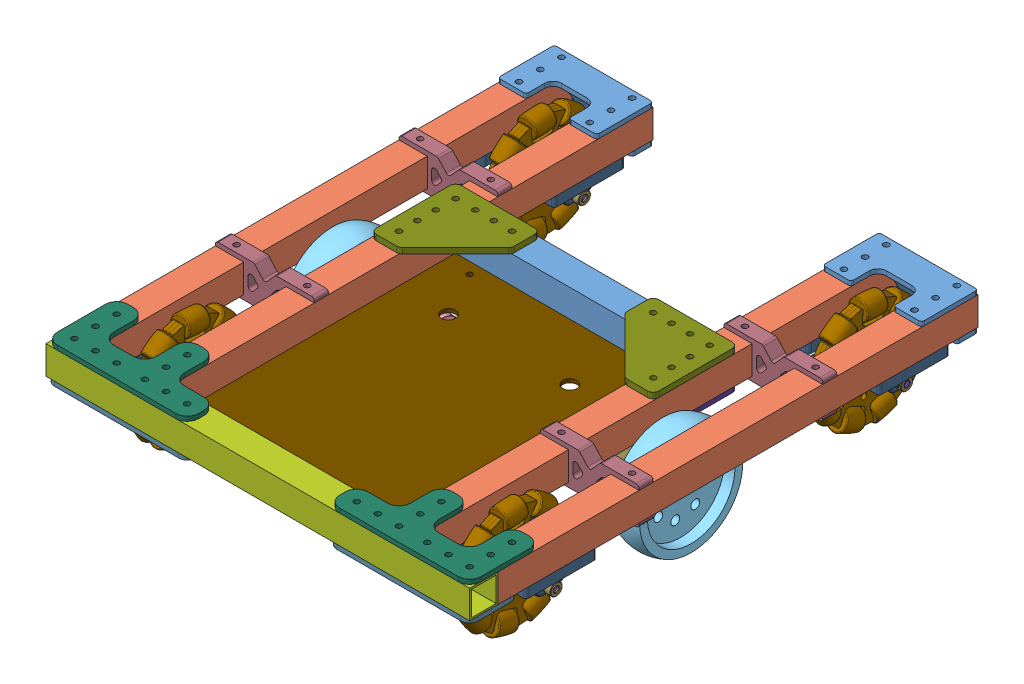
SolidWorks assembly Robot REV1, configuration Default. Lengths in mm.
Overall size (381 144.74 473.22).
69 component instances, 19 part files, 96 mates.
Components (placement in the parent):
- 1AL_8in-1: 1AL_8in [Default] at (-101.6 12.7 12.7) x (0 -1 0) z (0 0 1) size (25.4 203.2 25.4)
- 1AL_17in-1: 1AL_17in [Default] at (-114.3 12.7 -152.4) x (0 1 0) z (1 0 0) size (25.4 431.8 25.4)
- 1AL_17in-2: 1AL_17in [Default] at (114.3 12.7 279.4) x (0 -1 0) z (1 0 0) size (25.4 431.8 25.4)
- 1AL_17in-3: 1AL_17in [Default] at (-177.8 12.7 -152.4) x (0 1 0) z (1 0 0) size (25.4 431.8 25.4)
- 1AL_17in-4: 1AL_17in [Default] at (177.8 12.7 -152.4) x (1 0 0) z (0 -1 0) size (25.4 431.8 25.4)
- Motor mount-1: Motor mount [Default] at (114.7005 -22.3859 87.3407) x (0 0 -1) z (-1 0 0) size (72 44.98 12.7)
- 39530_txm-dc gearhead motor-1: 39530_txm-dc gearhead motor [Default] at (105 -22.5 76.2) x (0 0 1) z (0 1 0) size (37 99.15 37)
- 39055_txm-4 inch wheel-1: 39055_txm-4 inch wheel [Default] at (153.6244 -15.0231 100.1157) x (0 0.83426 0.551371) z (-1 0 0) size (97.6 97.6 25.4)
- 39079_txm-motor shaft hub with set screw-1: 39079_txm-motor shaft hub with set screw [Default] at (156.6976 -41.8931 64.5973) x (0 -0.551371 0.83426) z (-1 0 0) size (22 22 9.4)
- 39530_txm-dc gearhead motor-2: 39530_txm-dc gearhead motor [Default] at (-105 -22.5 76.2) x (0 0 -1) z (0 1 0) size (37 99.15 37)
- 39079_txm-motor shaft hub with set screw-2: 39079_txm-motor shaft hub with set screw [Default] at (-156.6976 -44.8973 83.3507) x (0 -0.263172 -0.964749) z (1 0 0) size (22 22 9.4)
- Motor mount-4: Motor mount [Default] at (-126.5995 -22.3859 87.3407) x (0 0 -1) z (-1 0 0) size (72 44.98 12.7)
- 39055_txm-4 inch wheel-2: 39055_txm-4 inch wheel [Default] at (-143.2256 -24.601 48.6766) x (0 -0.263172 -0.964749) z (-1 0 0) size (97.6 97.6 25.4)
- 1AL_15-2: 1AL_15 [Default] at (-190.5 12.7 292.1) x (0 -1 0) z (0 0 1) size (25.4 381 25.4)
- Omniwheel set-1: Omniwheel set [Default] at (-107.6288 -16.637 -92.837) x (0 0 -1) z (1 0 0) size (140.97 139.61 88.9)
  - 3in_Axel-1: 3in_Axel [Default] at (2.413 -2.413 -76.2) x (0.958428 0.285334 0) z (0.285334 -0.958428 0) size (4.83 76.2 4.83)
  - 4 inch omniwheel-2: 4 inch omniwheel [Default] at (5.0047 -4.3489 -46.041) x (-0.696661 0.7174 0) z (-0.7174 -0.696661 0) size (103.44 22.06 104.38)
  - 39079_txm-motor shaft hub with set screw-1: 39079_txm-motor shaft hub with set screw [Default] at (16.4027 7.2046 -45.1063) x (-0.696661 0.7174 0) z (0 0 1) size (22 22 9.4)
  - Omniwheel block-1: Omniwheel block [Default] at (2.413 16.637 -57.4712) x (1 0 0) z (0 1 0) size (63.5 25.4 27.33)
  - Wheel bushing-1: Wheel bushing [Default] at (-0.0381 -2.413 -57.046) size (9.52 9.53 12.7)
  - 39092_txm-axlesetcollars-1: 39092_txm-axlesetcollars [Default] at (2.6462 -2.783 -72.9038) x (0.992781 0.11994 0) z (0 0 1) size (11.66 11 6.2)
  - Omniwheel block-2: Omniwheel block [Default] at (2.413 16.637 -19.3712) x (-1 0 0) z (0 1 0) size (63.5 25.4 27.33)
  - Wheel bushing-2: Wheel bushing [Default] at (-0.0381 -2.413 -19.7964) x (1 0 0) z (0 0 -1) size (9.52 9.53 12.7)
  - 39092_txm-axlesetcollars-2: 39092_txm-axlesetcollars [Default] at (2.6002 -2.8083 -1.2602) size (11.66 11 6.2)
- Omniwheel set-2: Omniwheel set [Default] at (184.4712 -16.637 224.663) x (0 0 -1) z (1 0 0) size (140.97 139.61 88.9)
  - 3in_Axel-1: 3in_Axel [Default] at (2.413 -2.413 -76.2) x (0.958428 0.285334 0) z (0.285334 -0.958428 0) size (4.83 76.2 4.83)
  - 4 inch omniwheel-2: 4 inch omniwheel [Default] at (5.0047 -4.3489 -46.041) x (-0.696661 0.7174 0) z (-0.7174 -0.696661 0) size (103.44 22.06 104.38)
  - 39079_txm-motor shaft hub with set screw-1: 39079_txm-motor shaft hub with set screw [Default] at (16.4027 7.2046 -45.1063) x (-0.696661 0.7174 0) z (0 0 1) size (22 22 9.4)
  - Omniwheel block-1: Omniwheel block [Default] at (2.413 16.637 -57.4712) x (1 0 0) z (0 1 0) size (63.5 25.4 27.33)
  - Wheel bushing-1: Wheel bushing [Default] at (-0.0381 -2.413 -57.046) size (9.52 9.53 12.7)
  - 39092_txm-axlesetcollars-1: 39092_txm-axlesetcollars [Default] at (2.6462 -2.783 -72.9038) x (0.992781 0.11994 0) z (0 0 1) size (11.66 11 6.2)
  - Omniwheel block-2: Omniwheel block [Default] at (2.413 16.637 -19.3712) x (-1 0 0) z (0 1 0) size (63.5 25.4 27.33)
  - Wheel bushing-2: Wheel bushing [Default] at (-0.0381 -2.413 -19.7964) x (1 0 0) z (0 0 -1) size (9.52 9.53 12.7)
  - 39092_txm-axlesetcollars-2: 39092_txm-axlesetcollars [Default] at (2.6002 -2.8083 -1.2602) size (11.66 11 6.2)
- Omniwheel set-3: Omniwheel set [Default] at (107.6288 -16.637 -97.663) x (0 0 1) z (-1 0 0) size (140.97 139.61 88.9)
  - 3in_Axel-1: 3in_Axel [Default] at (2.413 -2.413 -76.2) x (0.958428 0.285334 0) z (0.285334 -0.958428 0) size (4.83 76.2 4.83)
  - 4 inch omniwheel-2: 4 inch omniwheel [Default] at (5.0047 -4.3489 -46.041) x (-0.696661 0.7174 0) z (-0.7174 -0.696661 0) size (103.44 22.06 104.38)
  - 39079_txm-motor shaft hub with set screw-1: 39079_txm-motor shaft hub with set screw [Default] at (16.4027 7.2046 -45.1063) x (-0.696661 0.7174 0) z (0 0 1) size (22 22 9.4)
  - Omniwheel block-1: Omniwheel block [Default] at (2.413 16.637 -57.4712) x (1 0 0) z (0 1 0) size (63.5 25.4 27.33)
  - Wheel bushing-1: Wheel bushing [Default] at (-0.0381 -2.413 -57.046) size (9.52 9.53 12.7)
  - 39092_txm-axlesetcollars-1: 39092_txm-axlesetcollars [Default] at (2.6462 -2.783 -72.9038) x (0.992781 0.11994 0) z (0 0 1) size (11.66 11 6.2)
  - Omniwheel block-2: Omniwheel block [Default] at (2.413 16.637 -19.3712) x (-1 0 0) z (0 1 0) size (63.5 25.4 27.33)
  - Wheel bushing-2: Wheel bushing [Default] at (-0.0381 -2.413 -19.7964) x (1 0 0) z (0 0 -1) size (9.52 9.53 12.7)
  - 39092_txm-axlesetcollars-2: 39092_txm-axlesetcollars [Default] at (2.6002 -2.8083 -1.2602) size (11.66 11 6.2)
- Omniwheel set-4: Omniwheel set [Default] at (-184.4712 -16.637 219.837) x (0 0 1) z (-1 0 0) size (140.97 139.61 88.9)
  - 3in_Axel-1: 3in_Axel [Default] at (2.413 -2.413 -76.2) x (0.958428 0.285334 0) z (0.285334 -0.958428 0) size (4.83 76.2 4.83)
  - 4 inch omniwheel-2: 4 inch omniwheel [Default] at (5.0047 -4.3489 -46.041) x (-0.696661 0.7174 0) z (-0.7174 -0.696661 0) size (103.44 22.06 104.38)
  - 39079_txm-motor shaft hub with set screw-1: 39079_txm-motor shaft hub with set screw [Default] at (16.4027 7.2046 -45.1063) x (-0.696661 0.7174 0) z (0 0 1) size (22 22 9.4)
  - Omniwheel block-1: Omniwheel block [Default] at (2.413 16.637 -57.4712) x (1 0 0) z (0 1 0) size (63.5 25.4 27.33)
  - Wheel bushing-1: Wheel bushing [Default] at (-0.0381 -2.413 -57.046) size (9.52 9.53 12.7)
  - 39092_txm-axlesetcollars-1: 39092_txm-axlesetcollars [Default] at (2.6462 -2.783 -72.9038) x (0.992781 0.11994 0) z (0 0 1) size (11.66 11 6.2)
  - Omniwheel block-2: Omniwheel block [Default] at (2.413 16.637 -19.3712) x (-1 0 0) z (0 1 0) size (63.5 25.4 27.33)
  - Wheel bushing-2: Wheel bushing [Default] at (-0.0381 -2.413 -19.7964) x (1 0 0) z (0 0 -1) size (9.52 9.53 12.7)
  - 39092_txm-axlesetcollars-2: 39092_txm-axlesetcollars [Default] at (2.6002 -2.8083 -1.2602) size (11.66 11 6.2)
- X Brace-1: X Brace [Default] at (-146.05 12.7 139.7) x (1 0 0) z (0 -1 0) size (88.9 12.7 33.4)
- X Brace-2: X Brace [Default] at (146.05 12.7 139.7) x (1 0 0) z (0 -1 0) size (88.9 12.7 33.4)
- X Brace-3: X Brace [Default] at (-146.05 12.7 -25.4) x (1 0 0) z (0 -1 0) size (88.9 12.7 33.4)
- X Brace-4: X Brace [Default] at (146.05 12.7 -25.4) x (1 0 0) z (0 -1 0) size (88.9 12.7 33.4)
- F Bracket1.0 3D-6: F Bracket1.0 3D [Default] at (0 -29.4 0) size (127 4 59.82)
- F Bracket1.0 3D-7: F Bracket1.0 3D [Default] at (0 25.4 0) x (-1 0 0) z (0 0 1) size (127 4 59.82)
- F Bracket D-5: F Bracket D [Default] at origin size (127 4 63.5)
- F Bracket D-6: F Bracket D [Default] at (0 54.8 0) x (-1 0 0) z (0 0 1) size (127 4 63.5)
- DXF L bracket-1: DXF L bracket [Default] at (127 25.4 0) x (-1 0 0) z (0 0 -1) size (76.2 5.08 76.2)
- DXF L bracket-2: DXF L bracket [Default] at (-127 25.4 0) x (0 0 1) z (-1 0 0) size (76.2 5.08 76.2)
- FIT bracket 3D-1: FIT bracket 3D [Default] at origin size (63.5 4 50.8)
- FIT bracket 3D-2: FIT bracket 3D [Default] at (0 -4 0) x (-1 0 0) z (0 0 1) size (63.5 4 50.8)
- ELE plexi-1: ELE plexi [Default] x (1 0 0) z (0 1 0) size (198.12 248.92 3.17)
- End Cap-1: End Cap [Default] at (177.8 25.4 -152.4) x (-1 0 0) z (0 1 0) size (88.9 50.8 33.4)
- End Cap-2: End Cap [Default] at (-114.3 25.4 -152.4) x (-1 0 0) z (0 1 0) size (88.9 50.8 33.4)
Mates (geometry in assembly coordinates):
- Coincident1: coincident anti-aligned: plane of 1AL_8in-1 through (101.6 0 0) normal (0 -1 0); plane of assembly through (0 0 0) normal (0 1 0)
- Coincident2: coincident anti-aligned: plane of 1AL_8in-1 through (101.6 0 0) normal (0 0 -1); plane of assembly through (0 0 0) normal (0 0 1)
- Distance2: distance = 101.6 mm anti-aligned: plane of assembly through (0 0 0) normal (1 0 0); plane of 1AL_8in-1 through (-101.6 12.7 12.7) normal (-1 0 0)
- Coincident4: coincident aligned: plane of 1AL_8in-1 through (101.6 25.4 0) normal (0 1 0); plane of 1AL_17in-1 through (-101.6 25.4 279.4) normal (0 1 0)
- Coincident5: coincident anti-aligned: plane of 1AL_8in-1 through (-101.6 12.7 12.7) normal (-1 0 0); plane of 1AL_17in-1 through (-101.6 25.4 279.4) normal (1 0 0)
- Coincident6: coincident aligned: plane of 1AL_8in-1 through (101.6 25.4 0) normal (0 1 0); plane of 1AL_17in-2 through (127 25.4 -152.4) normal (0 1 0)
- Coincident7: coincident anti-aligned: plane of 1AL_8in-1 through (101.6 12.7 12.7) normal (1 0 0); plane of 1AL_17in-2 through (101.6 0 -152.4) normal (-1 0 0)
- Coincident8: coincident aligned: plane of 1AL_17in-1 through (-114.3 12.7 -152.4) normal (0 0 -1); plane of 1AL_17in-2 through (114.3 12.7 -152.4) normal (0 0 -1)
- Distance3: distance = 152.4 mm aligned: plane of 1AL_17in-2 through (114.3 12.7 -152.4) normal (0 0 -1); plane of 1AL_8in-1 through (101.6 0 0) normal (0 0 -1)
- Distance4: distance = 38.1 mm anti-aligned: plane of 1AL_17in-1 through (-127 25.4 279.4) normal (-1 0 0); plane of 1AL_17in-3 through (-165.1 25.4 279.4) normal (1 0 0)
- Coincident11: coincident: line of 1AL_17in-1 through (-127 25.4 279.4) axis (0 0 -1); plane of 1AL_17in-3 through (-165.1 25.4 279.4) normal (0 1 0)
- Coincident12: coincident aligned: plane of 1AL_17in-1 through (-114.3 12.7 -152.4) normal (0 0 -1); plane of 1AL_17in-3 through (-177.8 12.7 -152.4) normal (0 0 -1)
- Coincident13: coincident aligned: plane of 1AL_17in-2 through (127 25.4 -152.4) normal (0 1 0); plane of 1AL_17in-4 through (190.5 25.4 279.4) normal (0 1 0)
- Coincident14: coincident aligned: plane of 1AL_17in-2 through (114.3 12.7 -152.4) normal (0 0 -1); plane of 1AL_17in-4 through (177.8 12.7 -152.4) normal (0 0 -1)
- Distance5: distance = 38.1 mm anti-aligned: plane of 1AL_17in-2 through (127 0 -152.4) normal (1 0 0); plane of 1AL_17in-4 through (165.1 0 279.4) normal (-1 0 0)
- Coincident49: coincident anti-aligned: plane of 1AL_17in-2 through (127 0 -152.4) normal (0 -1 0); plane of Motor mount-1 through (114.3 0 40.2) normal (0 1 0)
- Coincident50: coincident aligned: plane of 1AL_17in-2 through (127 0 -152.4) normal (1 0 0); plane of Motor mount-1 through (127 -22.5 76.2) normal (1 0 0)
- Concentric2: concentric anti-aligned: cylinder of Motor mount-1 through (114.3 -22.5 76.2) axis (1 0 0) radius 18.5; cylinder of 39530_txm-dc gearhead motor-1 through (60.5 -22.5 76.2) axis (-1 0 0) radius 18.5
- Coincident51: coincident aligned: plane of Motor mount-1 through (127 -22.5 76.2) normal (1 0 0); plane of 39530_txm-dc gearhead motor-1 through (127 -22.5 92.7) normal (1 0 0)
- Parallel3: parallel aligned: plane of 1AL_17in-2 through (127 0 -152.4) normal (0 -1 0); plane of 39530_txm-dc gearhead motor-1 through (158.001 -31.95 77.9313) normal (0 -1 0)
- Concentric3: concentric anti-aligned: cylinder of 39530_txm-dc gearhead motor-1 through (158 -29.5 76.2) axis (1 0 0) radius 3; cylinder of 39055_txm-4 inch wheel-1 through (161.125 -29.5 76.2) axis (-1 0 0) radius 4
- Coincident55: coincident anti-aligned: plane of 39055_txm-4 inch wheel-1 through (145.25 -29.5 76.2) normal (-1 0 0); plane of 39079_txm-motor shaft hub with set screw-1 through (145.25 -29.5 76.2) normal (1 0 0)
- Concentric8: concentric aligned: cylinder of 39055_txm-4 inch wheel-1 through (161.125 -29.5 76.2) axis (-1 0 0) radius 4; cylinder of 39079_txm-motor shaft hub with set screw-1 through (145.25 -29.5 76.2) axis (-1 0 0) radius 3.015
- Concentric9: concentric aligned: cylinder of 39055_txm-4 inch wheel-1 through (161.125 -36.1741 71.789) axis (-1 0 0) radius 1.75; cylinder of 39079_txm-motor shaft hub with set screw-1 through (145.25 -36.1741 71.789) axis (-1 0 0) radius 1.35
- Coincident56: coincident anti-aligned: plane of 39530_txm-dc gearhead motor-1 through (135.85 -29.5 76.2) normal (1 0 0); plane of 39079_txm-motor shaft hub with set screw-1 through (135.85 -29.5 76.2) normal (-1 0 0)
- Coincident59: coincident aligned: plane of 1AL_17in-1 through (-127 25.4 279.4) normal (-1 0 0); plane of Motor mount-4 through (-127 -22.5 76.2) normal (-1 0 0)
- Coincident60: coincident anti-aligned: plane of 1AL_17in-1 through (-101.6 0 279.4) normal (0 -1 0); plane of Motor mount-4 through (-127 0 40.2) normal (0 1 0)
- Concentric11: concentric aligned: cylinder of 39530_txm-dc gearhead motor-2 through (-60.5 -22.5 76.2) axis (1 0 0) radius 18.5; cylinder of Motor mount-4 through (-127 -22.5 76.2) axis (1 0 0) radius 18.5
- Coincident61: coincident aligned: plane of 39530_txm-dc gearhead motor-2 through (-127 -22.5 59.7) normal (-1 0 0); plane of Motor mount-4 through (-127 -22.5 76.2) normal (-1 0 0)
- Parallel5: parallel aligned: plane of 1AL_17in-1 through (-101.6 0 279.4) normal (0 -1 0); plane of 39530_txm-dc gearhead motor-2 through (-158.001 -31.95 74.4687) normal (0 -1 0)
- Concentric12: concentric anti-aligned: cylinder of 39530_txm-dc gearhead motor-2 through (-158 -29.5 76.2) axis (-1 0 0) radius 3; cylinder of 39079_txm-motor shaft hub with set screw-2 through (-145.25 -29.5 76.2) axis (1 0 0) radius 3.015
- Coincident64: coincident anti-aligned: plane of 39530_txm-dc gearhead motor-2 through (-135.85 -29.5 76.2) normal (-1 0 0); plane of 39079_txm-motor shaft hub with set screw-2 through (-135.85 -29.5 76.2) normal (1 0 0)
- Concentric13: concentric aligned: cylinder of 39530_txm-dc gearhead motor-2 through (-158 -29.5 76.2) axis (-1 0 0) radius 3; cylinder of 39055_txm-4 inch wheel-2 through (-135.725 -29.5 76.2) axis (-1 0 0) radius 4
- Coincident67: coincident anti-aligned: plane of 39079_txm-motor shaft hub with set screw-2 through (-145.25 -29.5 76.2) normal (-1 0 0); plane of 39055_txm-4 inch wheel-2 through (-145.25 -29.5 76.2) normal (1 0 0)
- Concentric14: concentric anti-aligned: cylinder of 39079_txm-motor shaft hub with set screw-2 through (-145.25 -37.218 78.3054) axis (1 0 0) radius 1.35; cylinder of 39055_txm-4 inch wheel-2 through (-135.725 -37.218 78.3054) axis (-1 0 0) radius 1.75
- Coincident68: coincident aligned: plane of 1AL_17in-3 through (-165.1 25.4 279.4) normal (0 1 0); plane of 1AL_15-2 through (190.5 25.4 279.4) normal (0 1 0)
- Coincident69: coincident aligned: plane of 1AL_17in-3 through (-190.5 25.4 279.4) normal (-1 0 0); plane of 1AL_15-2 through (-190.5 12.7 292.1) normal (-1 0 0)
- Coincident70: coincident anti-aligned: plane of 1AL_17in-3 through (-177.8 12.7 279.4) normal (0 0 1); plane of 1AL_15-2 through (190.5 0 279.4) normal (0 0 -1)
- Concentric15: concentric anti-aligned: cylinder of 39055_txm-4 inch wheel-1 through (145.25 -29.5 76.2) axis (-1 0 0) radius 39.37; cylinder of 39055_txm-4 inch wheel-2 through (-145.25 -29.5 76.2) axis (1 0 0) radius 39.37
- Coincident79: coincident anti-aligned: plane of 1AL_17in-3 through (-165.1 0 279.4) normal (0 -1 0); plane of Omniwheel set-1/Omniwheel block-1 through (-190.5 0 -127) normal (0 1 0)
- Coincident80: coincident aligned: plane of 1AL_17in-3 through (-190.5 25.4 279.4) normal (-1 0 0); plane of Omniwheel set-1/Omniwheel block-1 through (-190.5 0 -95.25) normal (-1 0 0)
- Distance6: distance = 25.4 mm aligned: plane of Omniwheel set-1/Omniwheel block-1 through (-190.5 -8.89 -127) normal (0 0 -1); plane of 1AL_17in-3 through (-177.8 12.7 -152.4) normal (0 0 -1)
- Coincident83: coincident anti-aligned: plane of 1AL_17in-3 through (-165.1 0 279.4) normal (0 -1 0); plane of Omniwheel set-4/Omniwheel block-1 through (-101.6 0 254) normal (0 1 0)
- Coincident84: coincident aligned: plane of 1AL_17in-3 through (-190.5 25.4 279.4) normal (-1 0 0); plane of Omniwheel set-4/Omniwheel block-2 through (-190.5 0 222.25) normal (-1 0 0)
- Distance7: distance = 25.4 mm: plane of Omniwheel set-4/Omniwheel block-2 through (-190.5 0 254) normal (0 0 1); line of 1AL_15-2 through (-190.5 0 279.4) axis (0 1 0)
- Coincident87: coincident anti-aligned: plane of 1AL_17in-2 through (127 0 -152.4) normal (0 -1 0); plane of Omniwheel set-2/Omniwheel block-2 through (190.5 0 254) normal (0 1 0)
- Coincident88: coincident aligned: plane of 1AL_17in-4 through (190.5 0 279.4) normal (1 0 0); plane of Omniwheel set-2/Omniwheel block-2 through (190.5 0 222.25) normal (1 0 0)
- Distance8: distance = 25.4 mm: line of 1AL_15-2 through (190.5 0 279.4) axis (0 1 0); plane of Omniwheel set-2/Omniwheel block-2 through (190.5 -8.89 254) normal (0 0 1)
- Coincident90: coincident aligned: plane of 1AL_17in-4 through (190.5 0 279.4) normal (1 0 0); plane of Omniwheel set-3/Omniwheel block-1 through (190.5 0 -95.25) normal (1 0 0)
- Distance9: distance = 25.4 mm aligned: plane of Omniwheel set-3/Omniwheel block-1 through (190.5 0 -127) normal (0 0 -1); plane of 1AL_17in-4 through (177.8 12.7 -152.4) normal (0 0 -1)
- Coincident92: coincident anti-aligned: plane of 1AL_17in-4 through (190.5 0 279.4) normal (0 -1 0); plane of Omniwheel set-3/Omniwheel block-1 through (190.5 0 -63.5) normal (0 1 0)
- Width5: width aligned: plane of 1AL_15-2 through (190.5 0 304.8) normal (0 0 1); plane of 1AL_17in-4 through (177.8 12.7 -152.4) normal (0 0 -1); plane of Motor mount-1 through (114.3 0 112.2) normal (0 0 1); plane of Motor mount-1 through (114.3 -22.5 40.2) normal (0 0 -1)
- Coincident100: coincident anti-aligned: plane of 1AL_17in-3 through (-165.1 25.4 279.4) normal (0 1 0); plane of X Brace-1 through (-165.1 25.4 152.4) normal (0 -1 0)
- Coincident101: coincident anti-aligned: plane of 1AL_17in-3 through (-165.1 25.4 279.4) normal (1 0 0); plane of X Brace-1 through (-165.1 0 152.4) normal (-1 0 0)
- Distance10: distance = 127 mm anti-aligned: plane of 1AL_15-2 through (190.5 0 279.4) normal (0 0 -1); plane of X Brace-1 through (-146.05 12.7 152.4) normal (0 0 1)
- Coincident103: coincident aligned: plane of 1AL_17in-2 through (127 25.4 -152.4) normal (0 1 0); circle of X Brace-2
- Coincident104: coincident anti-aligned: plane of 1AL_17in-2 through (127 0 -152.4) normal (1 0 0); plane of X Brace-2 through (127 0 152.4) normal (-1 0 0)
- Coincident105: coincident aligned: plane of X Brace-1 through (-146.05 12.7 152.4) normal (0 0 1); plane of X Brace-2 through (146.05 12.7 152.4) normal (0 0 1)
- Coincident107: coincident anti-aligned: plane of 1AL_17in-3 through (-165.1 25.4 279.4) normal (0 1 0); plane of X Brace-3 through (-165.1 25.4 -12.7) normal (0 -1 0)
- Coincident110: coincident anti-aligned: plane of 1AL_17in-3 through (-165.1 25.4 279.4) normal (1 0 0); plane of X Brace-3 through (-165.1 0 -12.7) normal (-1 0 0)
- Distance11: distance = 127 mm aligned: plane of 1AL_17in-3 through (-177.8 12.7 -152.4) normal (0 0 -1); plane of X Brace-3 through (-146.05 12.7 -25.4) normal (0 0 -1)
- Coincident112: coincident anti-aligned: plane of 1AL_17in-4 through (190.5 25.4 279.4) normal (0 1 0); plane of X Brace-4 through (165.1 25.4 -12.7) normal (0 -1 0)
- Coincident113: coincident anti-aligned: plane of 1AL_17in-4 through (165.1 0 279.4) normal (-1 0 0); plane of X Brace-4 through (165.1 0 -12.7) normal (1 0 0)
- Distance12: distance = 127 mm aligned: plane of X Brace-4 through (146.05 12.7 -25.4) normal (0 0 -1); plane of 1AL_17in-4 through (177.8 12.7 -152.4) normal (0 0 -1)
- Coincident115: coincident anti-aligned: plane of 1AL_15-2 through (190.5 0 279.4) normal (0 -1 0); plane of F Bracket1.0 3D-6 through (0 0 0) normal (0 1 0)
- Coincident116: coincident aligned: plane of 1AL_17in-3 through (-190.5 25.4 279.4) normal (-1 0 0); plane of F Bracket1.0 3D-6 through (-190.5 0 0) normal (-1 0 0)
- Coincident117: coincident aligned: plane of 1AL_15-2 through (190.5 0 304.8) normal (0 0 1); plane of F Bracket1.0 3D-6 through (0 0 304.8) normal (0 0 1)
- Coincident1211: coincident anti-aligned: plane of 1AL_15-2 through (190.5 0 279.4) normal (0 -1 0); plane of F Bracket1.0 3D-7 through (0 0 0) normal (0 1 0)
- Coincident122: coincident aligned: plane of 1AL_15-2 through (190.5 0 304.8) normal (0 0 1); plane of F Bracket1.0 3D-7 through (0 -4 304.8) normal (0 0 1)
- Coincident123: coincident aligned: plane of 1AL_15-2 through (190.5 12.7 292.1) normal (1 0 0); plane of F Bracket1.0 3D-7 through (190.5 -4 0) normal (1 0 0)
- Coincident124: coincident anti-aligned: plane of 1AL_15-2 through (190.5 25.4 279.4) normal (0 1 0); plane of F Bracket D-5 through (0 25.4 0) normal (0 -1 0)
- Coincident125: coincident aligned: plane of 1AL_15-2 through (190.5 0 304.8) normal (0 0 1); plane of F Bracket D-5 through (0 29.4 304.8) normal (0 0 1)
- Coincident126: coincident aligned: plane of 1AL_15-2 through (-190.5 12.7 292.1) normal (-1 0 0); plane of F Bracket D-5 through (-190.5 29.4 0) normal (-1 0 0)
- Coincident1271: coincident anti-aligned: plane of 1AL_15-2 through (190.5 25.4 279.4) normal (0 1 0); plane of F Bracket D-6 through (0 25.4 0) normal (0 -1 0)
- Coincident128: coincident aligned: plane of 1AL_15-2 through (190.5 0 304.8) normal (0 0 1); plane of F Bracket D-6 through (0 25.4 304.8) normal (0 0 1)
- Coincident129: coincident aligned: plane of 1AL_15-2 through (190.5 12.7 292.1) normal (1 0 0); plane of F Bracket D-6 through (190.5 25.4 0) normal (1 0 0)
- Coincident130: coincident aligned: plane of 1AL_17in-2 through (127 0 -152.4) normal (1 0 0); plane of DXF L bracket-1 through (127 30.48 0) normal (1 0 0)
- Coincident131: coincident anti-aligned: plane of 1AL_17in-2 through (127 25.4 -152.4) normal (0 1 0); plane of DXF L bracket-1 through (127 25.4 0) normal (0 -1 0)
- Coincident132: coincident aligned: plane of 1AL_8in-1 through (101.6 0 0) normal (0 0 -1); plane of DXF L bracket-1 through (50.8 30.48 0) normal (0 0 -1)
- Coincident134: coincident aligned: plane of 1AL_8in-1 through (101.6 25.4 0) normal (0 1 0); circle of DXF L bracket-2
- Coincident136: coincident aligned: plane of 1AL_8in-1 through (101.6 0 0) normal (0 0 -1); plane of DXF L bracket-2 through (-127 30.48 0) normal (0 0 -1)
- Coincident137: coincident aligned: plane of 1AL_17in-1 through (-127 25.4 279.4) normal (-1 0 0); plane of DXF L bracket-2 through (-127 30.48 76.2) normal (-1 0 0)
- Coincident138: coincident aligned: plane of 1AL_17in-1 through (-127 25.4 279.4) normal (-1 0 0); plane of FIT bracket 3D-2 through (-127 0 0) normal (-1 0 0)
- Coincident139: coincident anti-aligned: plane of 1AL_8in-1 through (101.6 0 0) normal (0 -1 0); plane of FIT bracket 3D-2 through (0 0 0) normal (0 1 0)
- Coincident140: coincident aligned: plane of 1AL_8in-1 through (101.6 0 0) normal (0 0 -1); plane of FIT bracket 3D-2 through (0 0 0) normal (0 0 -1)
- InPlace1: in place: plane of F Bracket1.0 3D-7 through (0 0 0) normal (0 1 0); plane of ELE plexi-1 through (0 0 0) normal (0 1 0); moOrthogonalPlaneRef_w of F Bracket1.0 3D-7 through (0 0 0) normal (0 1 0); plane of ELE plexi-1 through (0 0 0) normal (0 0 -1); plane of F Bracket1.0 3D-7 through (0 0 0) normal (0 1 0); unknown of ELE plexi-1; plane of F Bracket1.0 3D-7 through (0 0 0) normal (0 1 0); unknown of ELE plexi-1
- Coincident141: coincident aligned: plane of F Bracket1.0 3D-7; plane of ELE plexi-1
- Coincident142: coincident aligned: moOrthogonalPlaneRef_w of F Bracket1.0 3D-7 through (0 0 0) normal (0 0 -1); plane of ELE plexi-1 through (0 0 0) normal (0 0 -1)
- Coincident143: coincident anti-aligned: moOrthogonalPlaneRef_w of F Bracket1.0 3D-7 through (0 0 0) normal (-1 0 0); plane of ELE plexi-1
- InPlace2: in place: plane of 1AL_17in-4 through (190.5 25.4 279.4) normal (0 1 0); plane of ? through (0 25.4 0) normal (0 1 0); plane of 1AL_17in-4 through (190.5 25.4 279.4) normal (0 1 0); plane of ? through (0 25.4 0) normal (0 0 -1); plane of 1AL_17in-4 through (190.5 25.4 279.4) normal (0 1 0); unknown of ?; plane of 1AL_17in-4 through (190.5 25.4 279.4) normal (0 1 0); unknown of End Cap-1
- Coincident144: coincident aligned: plane of 1AL_17in-4; plane of End Cap-1
- Coincident145: coincident aligned: moOrthogonalPlaneRef_w of 1AL_17in-4 through (177.8 25.4 -152.4) normal (0 0 1); plane of End Cap-1
- Coincident146: coincident anti-aligned: moOrthogonalPlaneRef_w of 1AL_17in-4 through (177.8 25.4 -152.4) normal (1 0 0); plane of End Cap-1
- Coincident148: coincident anti-aligned: plane of 1AL_17in-1 through (-101.6 25.4 279.4) normal (0 1 0); plane of End Cap-2 through (-114.3 25.4 -152.4) normal (0 -1 0)
- Coincident149: coincident aligned: plane of 1AL_17in-1 through (-101.6 25.4 279.4) normal (1 0 0); plane of End Cap-2 through (-101.6 29.4 -152.4) normal (1 0 0)
- Coincident150: coincident aligned: plane of 1AL_17in-1 through (-114.3 12.7 -152.4) normal (0 0 -1); plane of End Cap-2 through (-114.3 29.4 -152.4) normal (0 0 -1)
